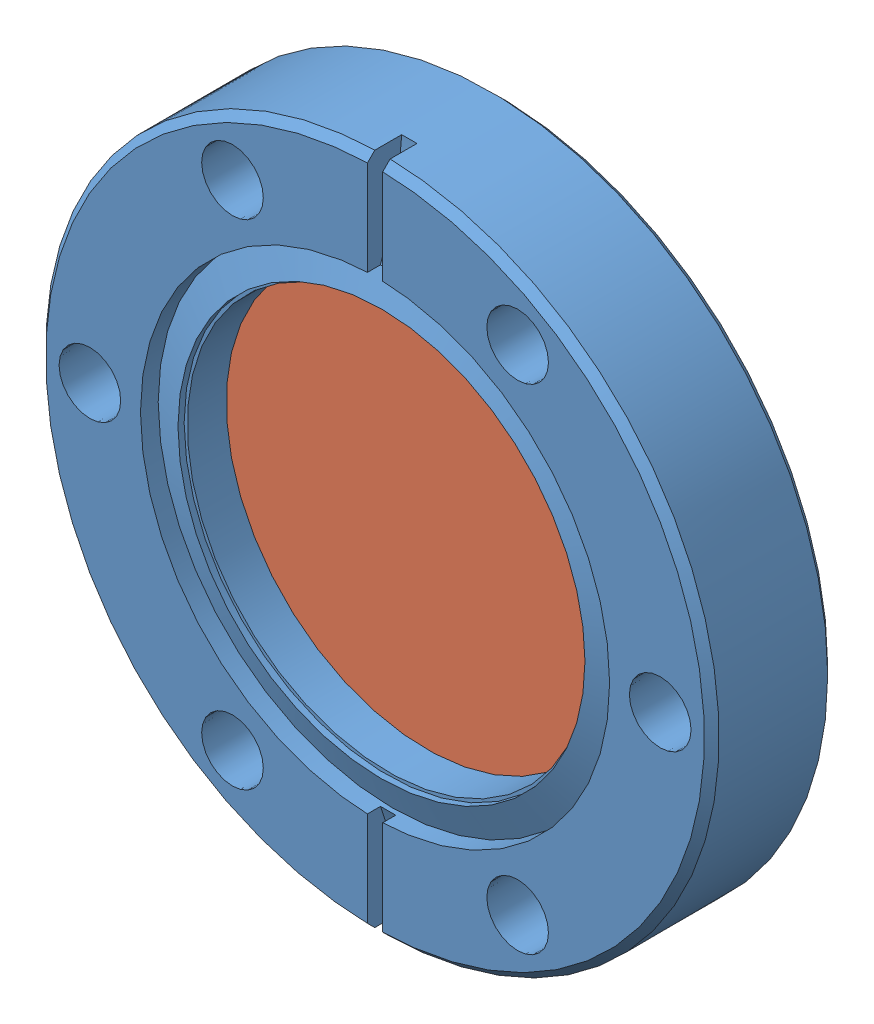
SolidWorks assembly 450002 (2.75 viewport), configuration Default. Lengths in mm.
Overall size (69.34 69.34 12.7).
2 component instances, 2 part files, 0 mates.
Components (placement in the parent):
- 130094-1: 130094 [Default] at (-8.8308 6.0802 -6.35) size (69.34 69.34 12.7)
- glass-1: glass [Default] at (-8.8308 6.0802 1.0414) x (-1 0 0) z (0 0 -1) size (44.7 44.7 5.08)
